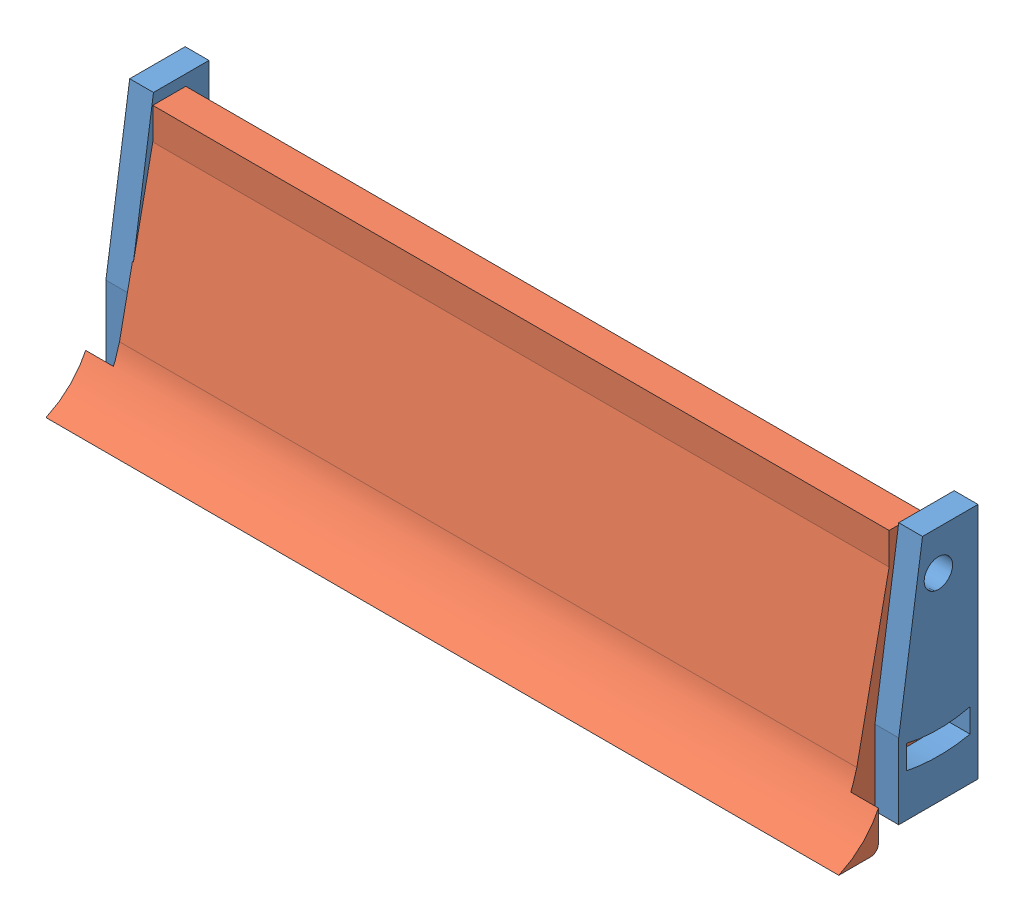
SolidWorks assembly Assem3, configuration Default. Lengths in mm.
Overall size (100.63 32.37 16.93).
2 component instances, 2 part files, 0 mates.
Components (placement in the parent):
- Part1-1: Part1 [Default] at (2.793 69.6966 83.085) size (100 30 10)
- Part2-1: Part2 [Default] at (2.1671 64.0605 81.8508) size (100 31 14)
